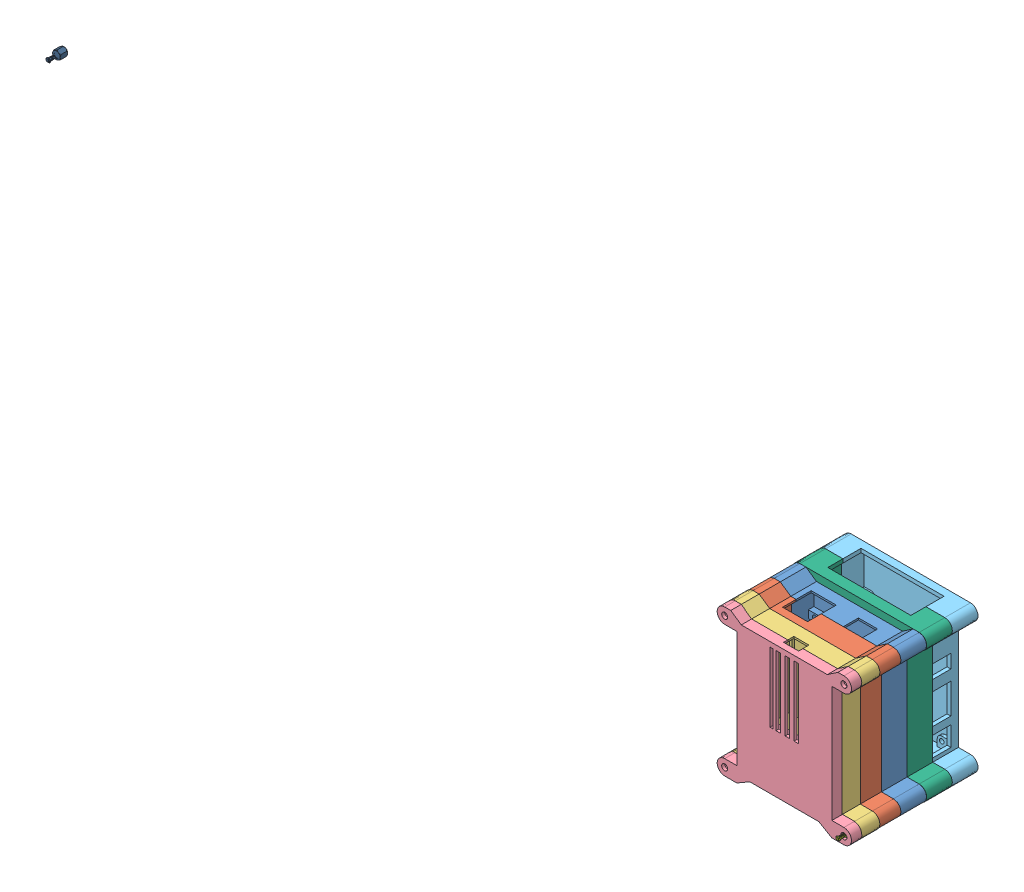
SolidWorks assembly 终极版, configuration 默认. Lengths in mm.
Overall size (679.34 110.09 155.75).
12 component instances, 10 part files, 19 mates.
Components (placement in the parent):
- 零件3-1: 零件3 [Default] at (-104.0828 -3.775 88.5) size (89 97 17)
- 零件4-1: 零件4 [Default] at (-104.0828 -3.775 117.5) size (89 97 14)
- 零件5-1: 零件5 [Default] at (-64.585 37.225 121.5) x (0 1 0) z (0 0 -1) size (97 89 12)
- 零件6-1: 零件6 [Default] at (-64.585 37.225 138.3167) x (0 1 0) z (0 0 -1) size (97 89 7)
- Bottom part-1: Bottom part [Default] at (-64.5806 37.225 54.5) x (0 1 0) z (1 0 0) size (97 17 89)
- Upper part-1: Upper part [Default] at (-64.5806 37.225 88.5) x (0 1 0) z (-1 0 0) size (97 17 89)
- Hex Spacer MF M3 L10mm-1: Hex Spacer MF M3 L10mm [默认] at (-65.063 -8.8158 71.5) size (35.27 35.27 35.27)
- Hex Spacer MF M3 L15mm.stp-1: Hex Spacer MF M3 L15mm.stp [默认] at (-115.2295 -8.4569 126.5) size (35.27 35.27 35.27)
- Hex Spacer MF M3 L20mm-1: Hex Spacer MF M3 L20mm [默认] at (-165.0791 -8.7898 91.5) size (35.27 35.27 37.7)
- Hex Spacer MF M3 L5mm-1: Hex Spacer MF M3 L5mm [默认] at (-659.1337 56.0446 16.0188) size (35.27 35.27 35.27)
- Hex Spacer MF M3 L20mm-2: Hex Spacer MF M3 L20mm [默认] at (-165.1431 -8.593 111.5) size (35.27 35.27 37.7)
- Hex Spacer MF M3 L10mm-2: Hex Spacer MF M3 L10mm [默认] at (-65.3265 -8.4029 136.5) size (35.27 35.27 35.27)
Mates (geometry in assembly coordinates):
- 重合1: coincident anti-aligned: plane of Bottom part-1 through (-25.0784 -8.775 71.5) normal (0 0 1); plane of Upper part-1 through (-104.0828 -8.775 71.5) normal (0 0 -1)
- 重合2: coincident anti-aligned: circle of Bottom part-1; circle of Upper part-1
- 重合3: coincident anti-aligned: circle of Bottom part-1; circle of Upper part-1
- 重合4: coincident anti-aligned: plane of 零件3-1 through (-104.0828 -8.775 88.5) normal (0 0 -1); plane of Upper part-1 through (-25.0784 -8.775 88.5) normal (0 0 1)
- 重合5: coincident anti-aligned: circle of 零件3-1; circle of Upper part-1
- 重合10: coincident anti-aligned: circle of 零件3-1; circle of Upper part-1
- 重合11: coincident anti-aligned: plane of 零件3-1 through (-104.0828 -3.775 105.5) normal (0 0 1); plane of 零件4-1 through (-104.0828 -3.775 105.5) normal (0 0 -1)
- 重合12: coincident aligned: circle of 零件3-1; circle of 零件4-1
- 重合13: coincident anti-aligned: plane of 零件4-1 through (-104.0828 78.225 119.5) normal (0 0 1); plane of 零件5-1 through (-25.0828 -8.775 119.5) normal (0 0 -1)
- 重合14: coincident aligned: circle of 零件4-1; circle of 零件5-1
- 重合17: coincident aligned: circle of 零件3-1; circle of 零件4-1
- 重合18: coincident aligned: circle of 零件4-1; circle of 零件5-1
- 同心1: concentric anti-aligned: circle of 零件5-1; circle of 零件6-1
- 同心2: concentric anti-aligned: circle of 零件5-1; circle of 零件6-1
- 锁定2: lock: unknown of Hex Spacer MF M3 L10mm-1; unknown of Hex Spacer MF M3 L20mm-1
- 锁定3: lock: unknown of Hex Spacer MF M3 L20mm-1; unknown of Hex Spacer MF M3 L20mm-2
- 锁定4: lock: unknown of Hex Spacer MF M3 L15mm.stp-1; unknown of Hex Spacer MF M3 L20mm-2
- 重合26: coincident anti-aligned: circle of Bottom part-1; plane of Hex Spacer MF M3 L10mm-1 through (-27.613 -11.3658 61.5) normal (0 0 -1)
- 锁定5: lock: unknown of Hex Spacer MF M3 L15mm.stp-1; unknown of Hex Spacer MF M3 L10mm-2
